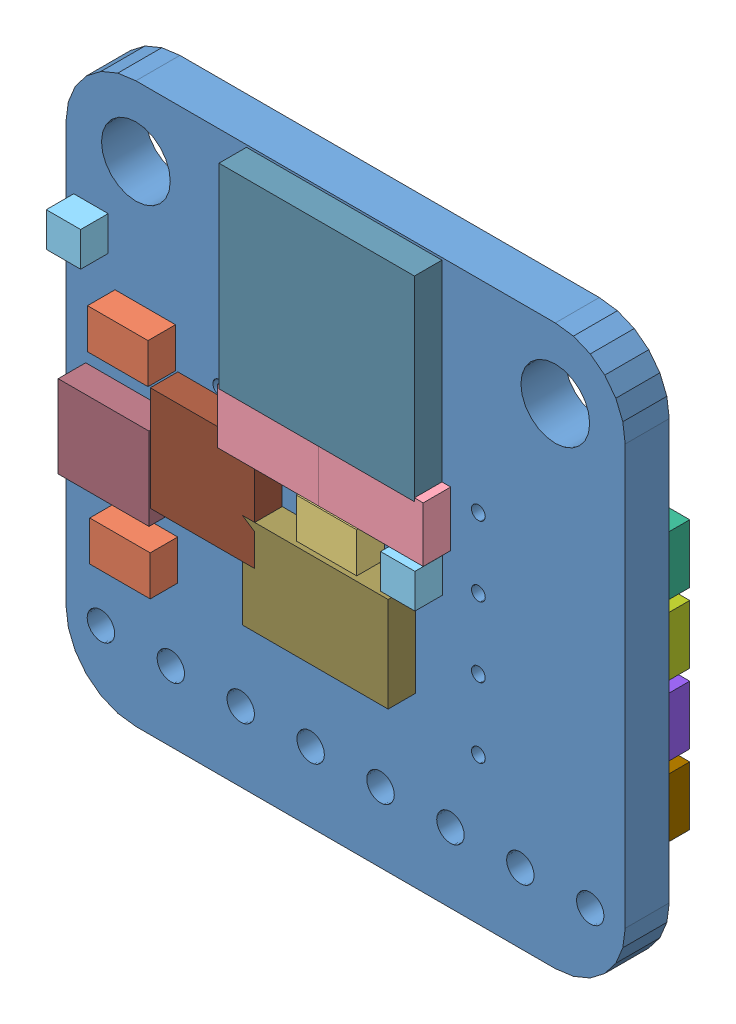
SolidWorks assembly adafruit max31850, configuration Default. Lengths in mm.
Overall size (20.32 20.32 3.6).
17 component instances, 14 part files, 0 mates.
Components (placement in the parent):
- adafruit max31850-1: adafruit max31850 [Default] at origin size (20.32 20.32 1.6)
- 0805NO_10UF-1: 0805NO_10UF [Default] at (2.968 6 1.6) x (-1 0 0) z (0 0 1) size (2.2 1.45 1)
- 0805NO_10UF-2: 0805NO_10UF [Default] at (2.874 12.638 1.6) size (2.2 1.45 1)
- 0805NO_0_1UF-1: 0805NO_0_1UF [Default] at (10.46 10.476 1.6) size (2.2 1.45 1)
- 0805_FERRITE-1: 0805_FERRITE [Default] at (8.4 12.257 1.6) size (3.8 2 1)
- 0805_FERRITE-2: 0805_FERRITE [Default] at (12.082 12.257 1.6) x (-1 0 0) z (0 0 1) size (3.8 2 1)
- FIDUCIAL_1MM_FIDUCIAL__-1: FIDUCIAL_1MM_FIDUCIAL__ [Default] at (13.43 9.952 1.6) size (1.25 1.25 1)
- FIDUCIAL_1MM_FIDUCIAL__-2: FIDUCIAL_1MM_FIDUCIAL__ [Default] at (1.283 14.636 1.6) size (1.25 1.25 1)
- SOLDERJUMPER_2WAY_OPEN_NOPASTE_SJ1_SOLDERJUMPER_2WAY_OPEN_NOPASTE-1: SOLDERJUMPER_2WAY_OPEN_NOPASTE_SJ1_SOLDERJUMPER_2WAY_OPEN_NOPASTE [Default] at (17.78 12.954 0) x (-1 0 0) z (0 0 -1) size (4.57 2.13 1)
- SOLDERJUMPER_2WAY_OPEN_NOPASTE_SJ2_SOLDERJUMPER_2WAY_OPEN_NOPASTE-1: SOLDERJUMPER_2WAY_OPEN_NOPASTE_SJ2_SOLDERJUMPER_2WAY_OPEN_NOPASTE [Default] at (17.78 10.414 0) x (-1 0 0) z (0 0 -1) size (4.57 2.13 1)
- SOLDERJUMPER_2WAY_OPEN_NOPASTE_SJ3_SOLDERJUMPER_2WAY_OPEN_NOPASTE-1: SOLDERJUMPER_2WAY_OPEN_NOPASTE_SJ3_SOLDERJUMPER_2WAY_OPEN_NOPASTE [Default] at (17.78 7.874 0) x (-1 0 0) z (0 0 -1) size (4.57 2.13 1)
- SOLDERJUMPER_2WAY_OPEN_NOPASTE_SJ4_SOLDERJUMPER_2WAY_OPEN_NOPASTE-1: SOLDERJUMPER_2WAY_OPEN_NOPASTE_SJ4_SOLDERJUMPER_2WAY_OPEN_NOPASTE [Default] at (17.78 5.334 0) x (-1 0 0) z (0 0 -1) size (4.57 2.13 1)
- ADAFRUIT_3_5MM_U_18_ADAFRUIT_3_5MM-1: ADAFRUIT_3_5MM_U_18_ADAFRUIT_3_5MM [Default] at (8.001 7.493 0) x (-1 0 0) z (0 0 -1) size (3.79 3.79 1)
- ADAFRUIT_3_5MM_U_19_ADAFRUIT_3_5MM-1: ADAFRUIT_3_5MM_U_19_ADAFRUIT_3_5MM [Default] at (4.064 8.128 1.6) size (3.79 3.79 1)
- TDFN10_3X4MM_MAX31850-1: TDFN10_3X4MM_MAX31850 [Default] at (10.206 7.73 1.6) x (0 -1 0) z (0 0 1) size (3.45 5.3 1)
- SOT235_MIC52253_3-1: SOT235_MIC52253_3 [Default] at (2.366 9.034 1.6) size (3.3 3 1)
- TERMBLOCK_1X23_5MM_3_5MM-1: TERMBLOCK_1X23_5MM_3_5MM [Default] at (10.16 16.637 1.6) x (-1 0 0) z (0 0 1) size (7.1 7.1 1)
